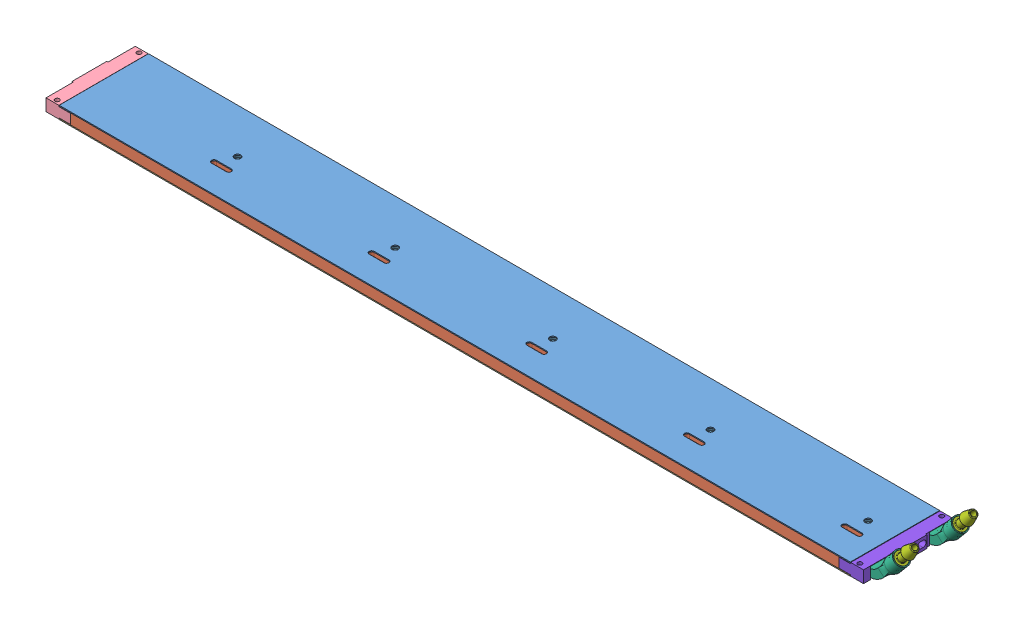
SolidWorks assembly 80W-svtx_lay_3-4_cooling_subassy, configuration Barrel 3. Lengths in mm.
Overall size (347.36 18.51 36.1).
22 component instances, 9 part files, 41 mates.
Components (placement in the parent):
- 80W-Barrel 3-4 Stave Skin 1-1: 80W-Barrel 3-4 Stave Skin 1 [Barrel 3] at (0 4.184 0) x (0 0 -1) z (1 0 0) size (36.1 0.41 319.8)
- 80W-Barrel 3-4 Stave Core-3: 80W-Barrel 3-4 Stave Core [Barrel 3] at origin size (310.46 4.18 36.1)
- 80W-Barrel 3-4 Stave Skin 2-1: 80W-Barrel 3-4 Stave Skin 2 [Barrel 3] x (1 0 0) z (0 -1 0) size (319.8 36.1 0.41)
- 80W-Barrel 3-4 stave mounting block u-end-4: 80W-Barrel 3-4 stave mounting block u-end [cooling end] at (-162.98 2.092 0) x (0 0 1) z (-1 0 0)
- rcc-board screw insert-1: rcc-board screw insert [default] at (-105.85 2.834 0) x (-1 0 0) z (0 0 1)
- rcc-board screw insert-2: rcc-board screw insert [default] at (-42.13 2.834 0) x (-1 0 0) z (0 0 1)
- rcc-board screw insert-3: rcc-board screw insert [default] at (21.59 2.834 0) x (-1 0 0) z (0 0 1)
- rcc-board screw insert-4: rcc-board screw insert [default] at (85.31 2.834 0) x (-1 0 0) z (0 0 1)
- rcc-board screw insert-5: rcc-board screw insert [default] at (149.03 2.834 0) x (-1 0 0) z (0 0 1)
- Adhesive-1: Adhesive [Default] at origin
- 80W-Barrel 3-4 Stave cooling U tube-1: 80W-Barrel 3-4 Stave cooling U tube [barrel 3] at (30.931 1.6875 0) x (-1 0 0) z (0 0 -1) size (334.07 11.96 30.94)
- 80W-Barrel 3-4 barb fitting-1: 80W-Barrel 3-4 barb fitting [Default] at (174.425 10.1767 -11.875) x (-0.766044 0.642788 0) z (0 0 -1)
- 80W-Barrel 3-4 barb fitting-2: 80W-Barrel 3-4 barb fitting [Default] at (174.425 10.1767 11.875) x (0.766044 -0.642788 0) z (0 0 1)
- 80W-Barrel 3-4 stave mounting block cooling-end-2: 80W-Barrel 3-4 stave mounting block cooling-end [cooling end] at (162.98 2.092 0) x (0 0 -1) z (1 0 0)
- 80W-Barrel 3-4 stave mounting block cooling-end-3: 80W-Barrel 3-4 stave mounting block cooling-end [cooling end] at (-194.84 2.092 0) x (0 0 1) z (-1 0 0) (suppressed, hidden)
- 80W-Barrel 3-4 stave mounting block u-end-5: 80W-Barrel 3-4 stave mounting block u-end [cooling end] at (194.84 2.092 0) x (0 0 -1) z (1 0 0) (suppressed, hidden)
- rcc-board screw insert-7: rcc-board screw insert [default] at (-180.89 2.784 0) x (-1 0 0) z (0 0 1) (suppressed, hidden)
- rcc-board screw insert-8: rcc-board screw insert [default] at (-117.17 2.784 0) x (-1 0 0) z (0 0 1) (suppressed, hidden)
- rcc-board screw insert-9: rcc-board screw insert [default] at (-53.45 2.784 0) x (-1 0 0) z (0 0 1) (suppressed, hidden)
- rcc-board screw insert-10: rcc-board screw insert [default] at (10.27 2.784 0) x (-1 0 0) z (0 0 1) (suppressed, hidden)
- rcc-board screw insert-11: rcc-board screw insert [default] at (73.99 2.784 0) x (-1 0 0) z (0 0 1) (suppressed, hidden)
- rcc-board screw insert-12: rcc-board screw insert [default] at (137.71 2.784 0) x (-1 0 0) z (0 0 1) (suppressed, hidden)
Mates (geometry in assembly coordinates):
- Coincident3: coincident aligned: plane of 80W-Barrel 3-4 Stave Skin 2-1; plane of assembly
- Coincident5: coincident anti-aligned: unknown of ?
- Coincident35: coincident aligned: unknown of ?
- Coincident34: coincident aligned: plane of 80W-Barrel 3-4 Stave Skin 2-1 through (0 0 0) normal (0 0 1); plane of assembly
- Coincident36: coincident aligned: plane of ? through (0 0 0) normal (0 0 1)
- Coincident37: coincident aligned: plane of ? through (0 0 0) normal (1 0 0)
- Coincident60: coincident anti-aligned: plane of 80W-Barrel 3-4 Stave Skin 2-1 through (-159.9 0 -18.05) normal (0 1 0); plane of 80W-Barrel 3-4 Stave Core-3 through (160.23 0 -18.05) normal (0 -1 0)
- Coincident59: coincident anti-aligned: plane of 80W-Barrel 3-4 Stave Core-3 through (160.23 4.184 -18.05) normal (0 1 0); plane of 80W-Barrel 3-4 Stave Skin 1-1 through (159.9 4.184 18.05) normal (0 -1 0)
- Coincident54: coincident aligned: plane of 80W-Barrel 3-4 stave mounting block u-end-4 through (-162.98 2.092 0) normal (0 0 1); plane of assembly
- Parallel16: parallel aligned: plane of rcc-board screw insert-1 through (-105.85 2.834 0) normal (0 0 1); plane of assembly
- Concentric17: concentric: cylinder of rcc-board screw insert-1 through (-180.89 85.836 0) axis (0 1 0) radius 3; cylinder of 80W-Barrel 3-4 Stave Core-3 through (-105.85 75.7451 0) axis (0 1 0) radius 3.55
- Coincident62: coincident aligned: plane of 80W-Barrel 3-4 Stave Skin 1-1 through (0 4.184 0) normal (1 0 0); plane of assembly
- Coincident63: coincident anti-aligned: plane of 80W-Barrel 3-4 Stave Skin 1-1 through (0 4.184 0) normal (0 0 -1); plane of assembly
- Distance6: distance = 0.05 mm aligned: plane of rcc-board screw insert-1 through (-105.85 4.134 0) normal (0 1 0); plane of 80W-Barrel 3-4 Stave Core-3 through (160.23 4.184 -18.05) normal (0 1 0)
- Distance15: distance = 0.075 mm aligned: plane of 80W-Barrel 3-4 Stave Skin 1-1 through (159.9 4.592 18.05) normal (0 1 0); plane of 80W-Barrel 3-4 stave mounting block u-end-4 through (-155.23 4.517 -18.05) normal (0 1 0)
- Distance7: distance = 0.1 mm anti-aligned: plane of 80W-Barrel 3-4 Stave Skin 2-1 through (-159.9 0 -18.05) normal (0 1 0); plane of 80W-Barrel 3-4 Stave cooling U tube-1 through (-142.355 0.1 8.7) normal (0 -1 0)
- Coincident74: coincident anti-aligned: plane of 80W-Barrel 3-4 Stave cooling U tube-1 through (30.931 1.6875 0) normal (0 0 -1); plane of assembly
- Concentric19: concentric anti-aligned: cylinder of 80W-Barrel 3-4 barb fitting-2 through (171.2111 6.3464 11.875) axis (0.642788 0.766044 0) radius 2.4468; cylinder of 80W-Barrel 3-4 Stave cooling U tube-1 through (174.425 10.1767 11.875) axis (-0.642788 -0.766044 0) radius 2.5468
- Coincident75: coincident aligned: plane of 80W-Barrel 3-4 barb fitting-2 through (174.425 10.1767 11.875) normal (0.642788 0.766044 0); plane of 80W-Barrel 3-4 Stave cooling U tube-1 through (174.425 10.1767 11.875) normal (0.642788 0.766044 0)
- Coincident76: coincident aligned: plane of 80W-Barrel 3-4 barb fitting-1 through (174.425 10.1767 -11.875) normal (0.642788 0.766044 0); plane of 80W-Barrel 3-4 Stave cooling U tube-1 through (174.425 10.1767 -11.875) normal (0.642788 0.766044 0)
- Concentric20: concentric anti-aligned: cylinder of 80W-Barrel 3-4 barb fitting-1 through (171.2111 6.3464 -11.875) axis (0.642788 0.766044 0) radius 2.4468; cylinder of 80W-Barrel 3-4 Stave cooling U tube-1 through (174.425 10.1767 -11.875) axis (-0.642788 -0.766044 0) radius 2.5468
- Coincident94: coincident anti-aligned: plane of 80W-Barrel 3-4 stave mounting block u-end-4 through (-155.23 -0.333 -18.05) normal (1 0 0); plane of 80W-Barrel 3-4 Stave Core-3 through (-155.23 0 -18.05) normal (-1 0 0)
- Concentric21: concentric aligned: cylinder of rcc-board screw insert-1 through (-105.85 1.534 0) axis (0 1 0) radius 3; cylinder of 80W-Barrel 3-4 Stave Core-3 through (-105.85 -8.4155 0) axis (0 1 0) radius 3.5
- Distance14: distance = 0.075 mm aligned: plane of 80W-Barrel 3-4 Stave Skin 1-1 through (159.9 4.592 18.05) normal (0 1 0); plane of 80W-Barrel 3-4 stave mounting block cooling-end-2 through (155.23 4.517 18.05) normal (0 1 0)
- Coincident78: coincident anti-aligned: plane of 80W-Barrel 3-4 stave mounting block cooling-end-2 through (162.98 2.092 0) normal (0 0 -1)
- Coincident80: coincident anti-aligned: plane of 80W-Barrel 3-4 Stave Core-3 through (155.23 0 -18.05) normal (1 0 0); plane of 80W-Barrel 3-4 stave mounting block cooling-end-2 through (155.23 -0.333 18.05) normal (-1 0 0)
- Concentric22: concentric aligned: cylinder of 80W-Barrel 3-4 Stave Core-3 through (-142.355 0 0) axis (0 -1 0) radius 8.6; cylinder of 80W-Barrel 3-4 Stave cooling U tube-1 through (-142.355 1.6875 0) axis (0 -1 0) radius 15.05
- Coincident84: coincident aligned: plane of ? through (-315.641 117.2064 0) normal (0 0 1)
- Concentric23: concentric aligned: cylinder of 80W-Barrel 3-4 Stave Core-3 through (174.215 115.8999 0) axis (0 -1 0) radius 8.6; cylinder of 80W-Barrel 3-4 Stave cooling U tube-1 through (174.215 314.3971 0) axis (0 -1 0) radius 9.081
- Coincident85: coincident anti-aligned: plane of 80W-Barrel 3-4 Stave Core-3 through (-155.23 115.8999 -18.05) normal (-1 0 0); plane of 80W-Barrel 3-4 stave mounting block cooling-end-3 through (-187.09 -0.333 -18.05) normal (1 0 0)
- Distance12: distance = 0.075 mm aligned: plane of 80W-Barrel 3-4 Stave Skin 1-1 through (-196.89 4.592 -18.05) normal (0 1 0); plane of 80W-Barrel 3-4 stave mounting block cooling-end-3 through (-187.09 4.517 -18.05) normal (0 1 0)
- Coincident87: coincident aligned: plane of ? through (-162.98 117.9919 0) normal (0 0 1)
- Coincident88: coincident anti-aligned: plane of 80W-Barrel 3-4 Stave Core-3 through (155.23 115.8999 -18.05) normal (1 0 0); plane of 80W-Barrel 3-4 stave mounting block u-end-5 through (187.09 -5.068 18.05) normal (-1 0 0)
- Coincident89: coincident anti-aligned: plane of ? through (162.98 117.9919 0) normal (0 0 -1)
- Distance13: distance = 0.075 mm aligned: plane of 80W-Barrel 3-4 Stave Skin 1-1 through (-196.89 4.592 -18.05) normal (0 1 0); plane of 80W-Barrel 3-4 stave mounting block u-end-5 through (187.09 4.517 18.05) normal (0 1 0)
- Coincident91: coincident anti-aligned: plane of 80W-Barrel 3-4 Stave Core-3 through (-180.89 117.3839 0) normal (0 1 0); plane of rcc-board screw insert-7 through (-180.89 314.5746 0) normal (0 -1 0)
- Concentric24: concentric aligned: cylinder of 80W-Barrel 3-4 Stave Core-3 through (-180.89 117.3839 0) axis (0 1 0) radius 3.55; cylinder of rcc-board screw insert-7 through (-180.89 314.5746 0) axis (0 1 0) radius 3
- Coincident93: coincident anti-aligned: plane of 80W-Barrel 3-4 Stave Skin 2-1 through (0 0 0) normal (0 -1 0); plane of assembly
- Parallel17: parallel anti-aligned: plane of 80W-Barrel 3-4 barb fitting-1 through (174.425 10.1767 -11.875) normal (0 0 -1); plane of assembly
- Parallel18: parallel aligned: plane of 80W-Barrel 3-4 barb fitting-2 through (174.425 10.1767 11.875) normal (0 0 1); plane of assembly
- Parallel19: parallel aligned: plane of rcc-board screw insert-7 through (-180.89 2.784 0) normal (0 0 1); moBodyFeatRef_w of 80W-Barrel 3-4 stave mounting block cooling-end-2
